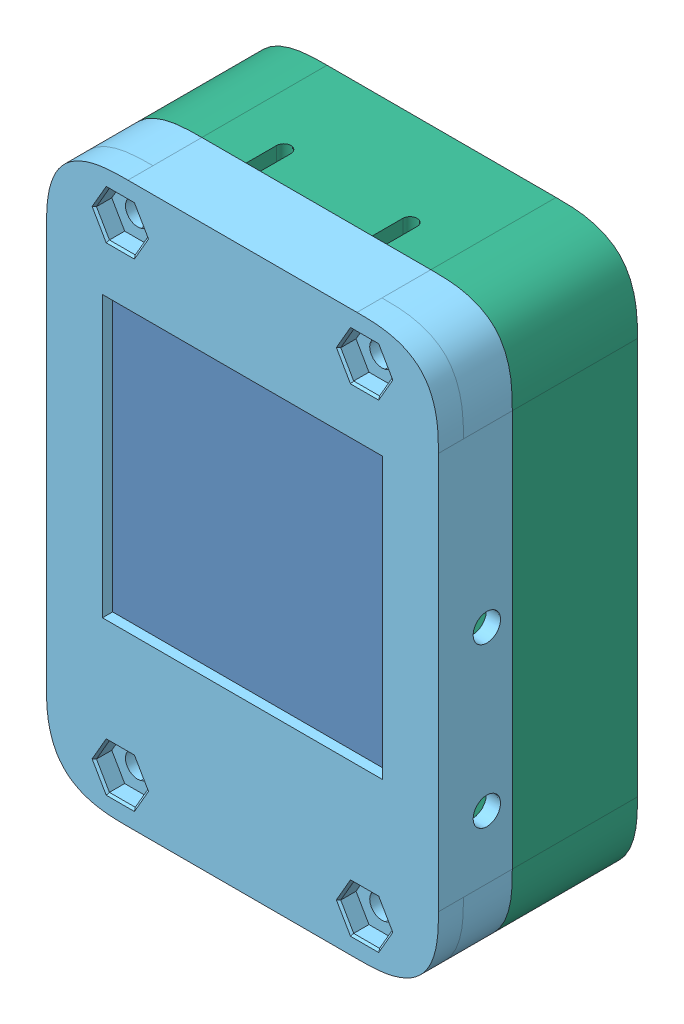
SolidWorks assembly DesktopScreen-v2, configuration 默认. Lengths in mm.
Overall size (38.6 55.1 19.61).
6 component instances, 6 part files, 18 mates.
Components (placement in the parent):
- Screen-1: Screen [默认] at origin size (34.1 38.57 3.51)
- PCB-1: PCB [默认] at (-127.0003 27.6011 -4.8001) size (34.53 36.97 7.06)
- Battery-1: Battery [默认] at (-15.788 -18.4873 -8.1) size (28 34.57 7)
- Subplate-1: Subplate [默认] x (-1 0 0) z (0 0 -1) size (35.3 40 4.8)
- Front Shell-v2-1: Front Shell-v2 [默认] at origin size (38.6 55.1 7.31)
- Back Shell-v2-1: Back Shell-v2 [默认] at (0 0 -4.8001) x (-1 0 0) z (0 0 -1) size (38.6 55.1 12.35)
Mates (geometry in assembly coordinates):
- 距离1: distance = 3.2 mm anti-aligned: plane of PCB-1 through (-1.788 0 -3.2) normal (0 0 1); plane of Screen-1 through (0 0 0) normal (0 0 -1)
- 宽度1: width anti-aligned: plane of PCB-1 through (-8.2004 -5.5624 -1.1799) normal (-1 0 0); plane of PCB-1 through (8.2004 -5.5624 -1.1799) normal (1 0 0); plane of Screen-1 through (7.25 -18.66 0.73) normal (1 0 0); plane of Screen-1 through (-7.25 -18.66 0.73) normal (-1 0 0)
- 宽度2: width aligned: plane of Screen-1 through (-15.9 18.66 0.98) normal (0 1 0); plane of Screen-1 through (-15.9 -18.66 0.98) normal (0 -1 0); plane of PCB-1 through (-15.288 18.4873 -4.8001) normal (0 1 0); plane of PCB-1 through (11.712 -18.4873 -4.8001) normal (0 -1 0)
- 在位2: in place: plane of ? through (0 0 0) normal (0 0 -1); plane of Subplate-1 through (0 0 0) normal (0 0 -1); moOrthogonalPlaneRef_w of ? through (0 0 0) normal (0 0 -1); plane of Subplate-1 through (0 0 0) normal (0 1 0); plane of ? through (0 0 0) normal (0 0 -1); plane of Subplate-1 through (0 0 0) normal (-1 0 0); plane of ? through (0 0 0) normal (0 0 -1); unknown of Subplate-1
- 重合1: coincident aligned: plane of Screen-1; plane of Subplate-1
- 重合2: coincident aligned: moOrthogonalPlaneRef_w of Screen-1 through (0 0 0) normal (0 1 0); plane of Subplate-1 through (0 0 0) normal (0 1 0)
- 重合3: coincident anti-aligned: moOrthogonalPlaneRef_w of Screen-1 through (0 0 0) normal (1 0 0); plane of Subplate-1 through (0 0 0) normal (-1 0 0)
- 宽度3: width aligned: plane of PCB-1 through (14.6993 15.5 -4.8001) normal (1 0 0); plane of Battery-1 through (-18.2753 -15.5 -4.8001) normal (-1 0 0); plane of PCB-1 through (12.212 -18.4873 -8.1) normal (1 0 0); plane of Battery-1 through (-15.788 -18.4873 -8.1) normal (-1 0 0)
- 重合5: coincident aligned: plane of PCB-1 through (11.712 -18.4873 -4.8001) normal (0 -1 0); plane of Battery-1 through (12.212 -18.4873 -15.1) normal (0 -1 0)
- 在位3: in place: plane of ? through (0 0 0) normal (0 0 1); plane of ? through (0 0 0) normal (0 1 0); plane of ? through (0 0 0) normal (1 0 0); unknown of ?
- 重合6: coincident aligned: 
- 重合7: coincident aligned: plane of Front Shell-v2-1 through (0 0 0) normal (0 1 0)
- 重合8: coincident anti-aligned: plane of Front Shell-v2-1 through (0 0 0) normal (1 0 0)
- 距离2: distance = 0.5 mm anti-aligned: plane of Battery-1 through (12.212 -18.4873 -8.1) normal (0 0 1); plane of PCB-1 through (-1.397 -5.5867 -7.6) normal (0 0 -1)
- 在位4: in place: plane of ? through (-1.788 0 -4.8001) normal (0 0 -1); plane of Back Shell-v2-1 through (0 0 -4.8001) normal (0 0 -1); plane of ? through (-1.788 0 -4.8001) normal (0 0 -1); plane of Back Shell-v2-1 through (0 0 -4.8001) normal (0 1 0); plane of ? through (-1.788 0 -4.8001) normal (0 0 -1); plane of Back Shell-v2-1 through (0 0 -4.8001) normal (-1 0 0); plane of ? through (-1.788 0 -4.8001) normal (0 0 -1); unknown of Back Shell-v2-1
- 重合10: coincident aligned: plane of Front Shell-v2-1; plane of Back Shell-v2-1
- 重合11: coincident aligned: moOrthogonalPlaneRef_w of Front Shell-v2-1 through (0 0 -4.8001) normal (0 1 0); plane of Back Shell-v2-1 through (0 0 -4.8001) normal (0 1 0)
- 重合12: coincident anti-aligned: moOrthogonalPlaneRef_w of Front Shell-v2-1 through (0 0 -4.8001) normal (1 0 0); plane of Back Shell-v2-1 through (0 0 -4.8001) normal (-1 0 0)
